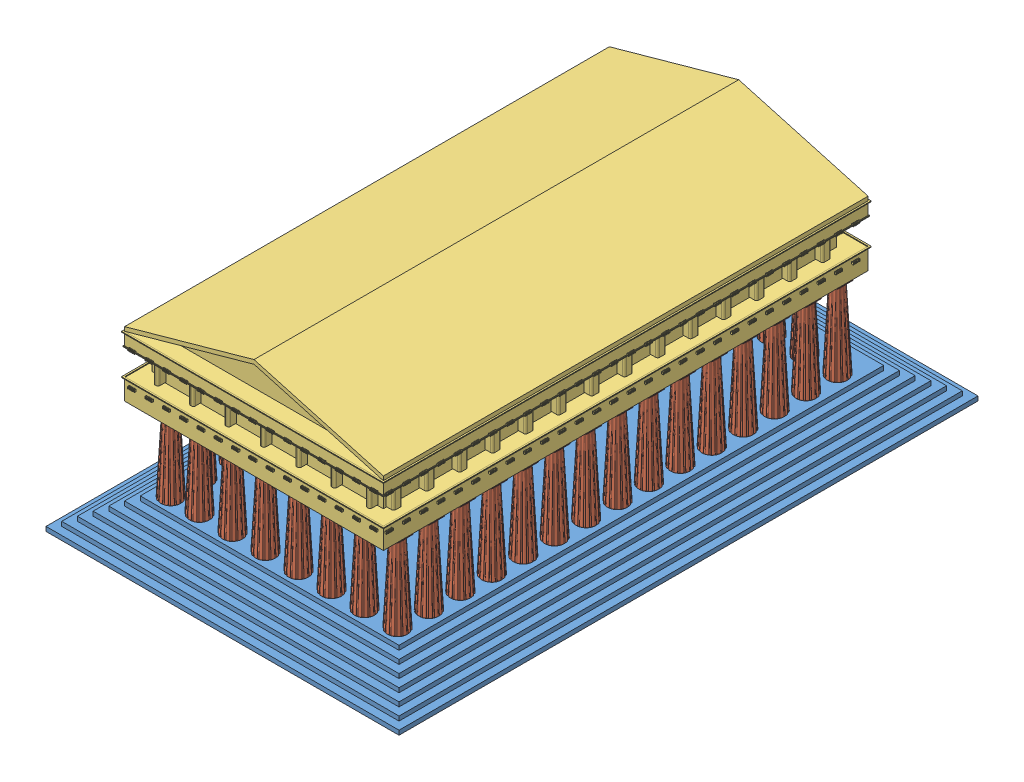
SolidWorks assembly ParthenonFinal_1to1000, configuration Default. Lengths in mm.
Overall size (44.94 27.46 73.7).
45 component instances, 3 part files, 4 mates.
Components (placement in the parent):
- parthenon_base-1: parthenon_base [Default] at (-11.0896 3.1982 28.3251) size (44.94 3.92 73.7)
- parthenon_pillar-2: parthenon_pillar [Default] at (9.9021 3.2982 -4.2756) x (1 0 0) z (0 1 0) size (2.62 2.64 10.72)
- parthenon_pillar-3: parthenon_pillar [Default] at (9.9021 3.2982 -8.2756) x (1 0 0) z (0 1 0) size (2.62 2.64 10.72)
- parthenon_pillar-4: parthenon_pillar [Default] at (9.9021 3.2982 -12.2756) x (1 0 0) z (0 1 0) size (2.62 2.64 10.72)
- parthenon_pillar-5: parthenon_pillar [Default] at (9.9021 3.2982 -16.2756) x (1 0 0) z (0 1 0) size (2.62 2.64 10.72)
- parthenon_pillar-6: parthenon_pillar [Default] at (9.9021 3.2982 -20.2756) x (1 0 0) z (0 1 0) size (2.62 2.64 10.72)
- parthenon_pillar-7: parthenon_pillar [Default] at (9.9021 3.2982 -24.2756) x (1 0 0) z (0 1 0) size (2.62 2.64 10.72)
- parthenon_pillar-8: parthenon_pillar [Default] at (9.9021 3.2982 -28.2756) x (1 0 0) z (0 1 0) size (2.62 2.64 10.72)
- parthenon_pillar-9: parthenon_pillar [Default] at (9.9021 3.2982 -32.2756) x (1 0 0) z (0 1 0) size (2.62 2.64 10.72)
- parthenon_pillar-10: parthenon_pillar [Default] at (9.9021 3.2982 -36.2756) x (1 0 0) z (0 1 0) size (2.62 2.64 10.72)
- parthenon_pillar-11: parthenon_pillar [Default] at (9.9021 3.2982 -40.2756) x (1 0 0) z (0 1 0) size (2.62 2.64 10.72)
- parthenon_pillar-12: parthenon_pillar [Default] at (9.9021 3.2982 -44.2756) x (1 0 0) z (0 1 0) size (2.62 2.64 10.72)
- parthenon_pillar-13: parthenon_pillar [Default] at (9.9021 3.2982 -48.2756) x (1 0 0) z (0 1 0) size (2.62 2.64 10.72)
- parthenon_pillar-14: parthenon_pillar [Default] at (9.9021 3.2982 -52.2756) x (1 0 0) z (0 1 0) size (2.62 2.64 10.72)
- parthenon_pillar-15: parthenon_pillar [Default] at (9.9021 3.2982 -56.2756) x (1 0 0) z (0 1 0) size (2.62 2.64 10.72)
- parthenon_pillar-16: parthenon_pillar [Default] at (9.9021 3.2982 -60.2756) x (1 0 0) z (0 1 0) size (2.62 2.64 10.72)
- parthenon_pillar-17: parthenon_pillar [Default] at (-18.9519 3.2982 -4.2756) x (1 0 0) z (0 1 0) size (2.62 2.64 10.72)
- parthenon_pillar-18: parthenon_pillar [Default] at (-18.9519 3.2982 -8.2756) x (1 0 0) z (0 1 0) size (2.62 2.64 10.72)
- parthenon_pillar-19: parthenon_pillar [Default] at (-18.9519 3.2982 -12.2756) x (1 0 0) z (0 1 0) size (2.62 2.64 10.72)
- parthenon_pillar-20: parthenon_pillar [Default] at (-18.9519 3.2982 -16.2756) x (1 0 0) z (0 1 0) size (2.62 2.64 10.72)
- parthenon_pillar-21: parthenon_pillar [Default] at (-18.9519 3.2982 -20.2756) x (1 0 0) z (0 1 0) size (2.62 2.64 10.72)
- parthenon_pillar-22: parthenon_pillar [Default] at (-18.9519 3.2982 -24.2756) x (1 0 0) z (0 1 0) size (2.62 2.64 10.72)
- parthenon_pillar-23: parthenon_pillar [Default] at (-18.9519 3.2982 -28.2756) x (1 0 0) z (0 1 0) size (2.62 2.64 10.72)
- parthenon_pillar-24: parthenon_pillar [Default] at (-18.9519 3.2982 -32.2756) x (1 0 0) z (0 1 0) size (2.62 2.64 10.72)
- parthenon_pillar-25: parthenon_pillar [Default] at (-18.9519 3.2982 -36.2756) x (1 0 0) z (0 1 0) size (2.62 2.64 10.72)
- parthenon_pillar-26: parthenon_pillar [Default] at (-18.9519 3.2982 -40.2756) x (1 0 0) z (0 1 0) size (2.62 2.64 10.72)
- parthenon_pillar-27: parthenon_pillar [Default] at (-18.9519 3.2982 -44.2756) x (1 0 0) z (0 1 0) size (2.62 2.64 10.72)
- parthenon_pillar-28: parthenon_pillar [Default] at (-18.9519 3.2982 -48.2756) x (1 0 0) z (0 1 0) size (2.62 2.64 10.72)
- parthenon_pillar-29: parthenon_pillar [Default] at (-18.9519 3.2982 -52.2756) x (1 0 0) z (0 1 0) size (2.62 2.64 10.72)
- parthenon_pillar-30: parthenon_pillar [Default] at (-18.9519 3.2982 -56.2756) x (1 0 0) z (0 1 0) size (2.62 2.64 10.72)
- parthenon_pillar-31: parthenon_pillar [Default] at (-18.9519 3.2982 -60.2756) x (1 0 0) z (0 1 0) size (2.62 2.64 10.72)
- parthenon_pillar-32: parthenon_pillar [Default] at (5.7021 3.2982 -4.2756) x (1 0 0) z (0 1 0) size (2.62 2.64 10.72)
- parthenon_pillar-33: parthenon_pillar [Default] at (1.5021 3.2982 -4.2756) x (1 0 0) z (0 1 0) size (2.62 2.64 10.72)
- parthenon_pillar-34: parthenon_pillar [Default] at (-2.6979 3.2982 -4.2756) x (1 0 0) z (0 1 0) size (2.62 2.64 10.72)
- parthenon_pillar-35: parthenon_pillar [Default] at (-6.8979 3.2982 -4.2756) x (1 0 0) z (0 1 0) size (2.62 2.64 10.72)
- parthenon_pillar-36: parthenon_pillar [Default] at (-11.0979 3.2982 -4.2756) x (1 0 0) z (0 1 0) size (2.62 2.64 10.72)
- parthenon_pillar-37: parthenon_pillar [Default] at (-15.2979 3.2982 -4.2756) x (1 0 0) z (0 1 0) size (2.62 2.64 10.72)
- parthenon_pillar-38: parthenon_pillar [Default] at (9.9021 3.2982 -60.2756) x (1 0 0) z (0 1 0) size (2.62 2.64 10.72)
- parthenon_pillar-39: parthenon_pillar [Default] at (5.7021 3.2982 -60.2756) x (1 0 0) z (0 1 0) size (2.62 2.64 10.72)
- parthenon_pillar-40: parthenon_pillar [Default] at (1.5021 3.2982 -60.2756) x (1 0 0) z (0 1 0) size (2.62 2.64 10.72)
- parthenon_pillar-41: parthenon_pillar [Default] at (-2.6979 3.2982 -60.2756) x (1 0 0) z (0 1 0) size (2.62 2.64 10.72)
- parthenon_pillar-42: parthenon_pillar [Default] at (-6.8979 3.2982 -60.2756) x (1 0 0) z (0 1 0) size (2.62 2.64 10.72)
- parthenon_pillar-43: parthenon_pillar [Default] at (-11.0979 3.2982 -60.2756) x (1 0 0) z (0 1 0) size (2.62 2.64 10.72)
- parthenon_pillar-44: parthenon_pillar [Default] at (-15.2979 3.2982 -60.2756) x (1 0 0) z (0 1 0) size (2.62 2.64 10.72)
- pillar_above-1: pillar_above [Default] at (62.4863 13.9232 -9.1936) size (33.34 12.82 62.1)
Mates (geometry in assembly coordinates):
- Coincident2: coincident anti-aligned: plane of parthenon_base-1 through (-11.0896 3.1982 28.3251) normal (0 1 0); plane of parthenon_pillar-2 through (17.7554 3.1982 26.6148) normal (0 -1 0)
- Distance1: distance = 0 mm anti-aligned: plane of pillar_above-1 through (62.4863 13.9232 -9.1936) normal (0 -1 0); plane of parthenon_pillar-2 through (9.9021 13.9232 -4.2756) normal (0 1 0)
- Parallel1: parallel aligned: line of parthenon_pillar-2 through (16.768 13.9232 27.6023) axis (1 0 0); line of pillar_above-1 through (-13.9935 13.9232 29.1023) axis (1 0 0)
- Distance2: distance = 2 mm aligned: plane of pillar_above-1 through (18.9465 15.8232 29.6023) normal (0 0 1); plane of parthenon_pillar-35 through (-0.032 13.9232 27.6023) normal (0 0 1)
